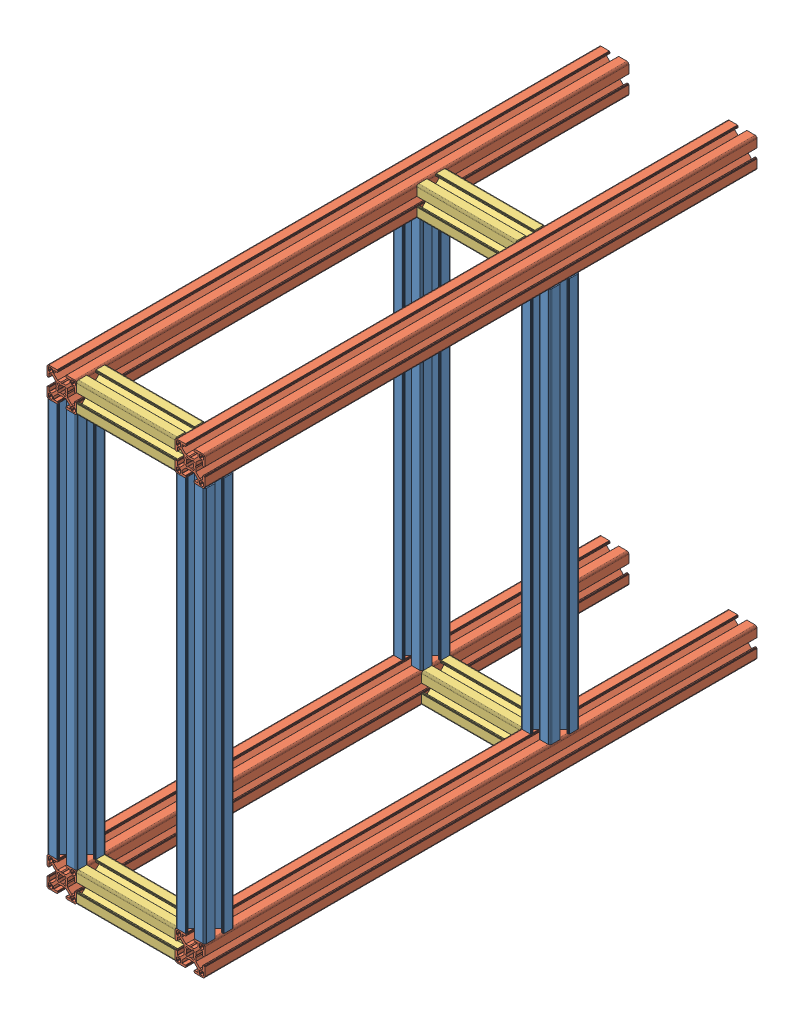
SolidWorks assembly module5_frame_v1.0, configuration Default. Lengths in mm.
Overall size (160 460 560).
12 component instances, 3 part files, 35 mates.
Components (placement in the parent):
- Profile_30x30mm_400mm-1: Profile_30x30mm_400mm [Default] x (1 0 0) z (0 -1 0) size (30 30 400)
- Profile_30x30mm_400mm-3: Profile_30x30mm_400mm [Default] at (-130 0 0) x (1 0 0) z (0 -1 0) size (30 30 400)
- profile_30x30mm_560mm-8: profile_30x30mm_560mm [Default] at (0 -30 30) size (30 30 560)
- profile_30x30mm_560mm-10: profile_30x30mm_560mm [Default] at (-130 -30 30) size (30 30 560)
- profile_30x30mm_560mm-6: profile_30x30mm_560mm [Default] at (-130 400 30) size (30 30 560)
- Profile_30x30mm_400mm-4: Profile_30x30mm_400mm [Default] at (30 400 -350) x (-1 0 0) z (0 1 0) size (30 30 400)
- profile_30x30mm_560mm-9: profile_30x30mm_560mm [Default] at (0 400 30) size (30 30 560)
- Profile_30x30mm_100mm-10: Profile_30x30mm_100mm [Default] at (0 400 30) x (0 0 -1) z (1 0 0) size (30 30 100)
- Profile_30x30mm_100mm-4: Profile_30x30mm_100mm [Default] at (0 400 -315) x (0 0 -1) z (1 0 0) size (30 30 100)
- Profile_30x30mm_100mm-11: Profile_30x30mm_100mm [Default] at (0 0 30) x (0 -1 0) z (1 0 0) size (30 30 100)
- Profile_30x30mm_100mm-9: Profile_30x30mm_100mm [Default] at (0 -30 -320) x (0 0 -1) z (1 0 0) size (30 30 100)
- Profile_30x30mm_400mm-5: Profile_30x30mm_400mm [Default] at (-130 0 -350) x (1 0 0) z (0 -1 0) size (30 30 400)
Mates (geometry in assembly coordinates):
- Coincident1: coincident: plane of Profile_30x30mm_400mm-1 through (0 400 0) normal (0 1 0); plane of ? through (-283.2452 400 0) normal (0 1 0)
- Coincident7: coincident: plane of Profile_30x30mm_400mm-1 through (10.25 400 30) normal (0 0 1); plane of ? through (-255.2452 400 30) normal (0 0 1)
- Coincident25: coincident: plane of profile_30x30mm_560mm-8 through (0 -30 30) normal (0 0 1); plane of ? through (-283.2452 -30 30) normal (0 0 1)
- Coincident26: coincident: plane of ? through (-283.2452 -30 30) normal (0 0 1); plane of ? through (-283.2452 400 30) normal (0 0 1)
- Coincident27: coincident: plane of ? through (-253.2452 -10.25 -530) normal (1 0 0); plane of ? through (-253.2452 419.75 -530) normal (1 0 0)
- Coincident30: coincident: plane of profile_30x30mm_560mm-8 through (10.25 0 -530) normal (0 1 0); plane of ? through (-272.9952 0 -530) normal (0 1 0)
- Coincident32: coincident: plane of assembly; plane of assembly; plane of Profile_30x30mm_400mm-1 through (30 400 2) normal (1 0 0); plane of profile_30x30mm_560mm-8 through (30 -28 -530) normal (1 0 0)
- Coincident35: coincident: plane of ? through (-283.2452 400 10.25) normal (-1 0 0); plane of ? through (-283.2452 428 -530) normal (-1 0 0)
- Coincident69: coincident: plane of assembly through (0 0 0) normal (0 1 0); plane of Profile_30x30mm_400mm-1 through (0 0 0) normal (0 -1 0); plane of assembly
- Coincident70: coincident: plane of assembly through (0 0 0) normal (0 0 1); plane of Profile_30x30mm_400mm-1 through (0 0 0) normal (0 0 1); plane of assembly
- Coincident71: coincident: plane of assembly through (0 0 0) normal (1 0 0); plane of Profile_30x30mm_400mm-1 through (0 0 0) normal (1 0 0); plane of assembly
- Coincident81: coincident: plane of assembly; plane of assembly; plane of Profile_30x30mm_400mm-1 through (30 400 19.75) normal (1 0 0); plane of profile_30x30mm_560mm-9 through (30 419.75 -530) normal (1 0 0)
- Distance36: distance = 30 mm: plane of assembly; plane of assembly; plane of Profile_30x30mm_400mm-1 through (0 0 0) normal (0 -1 0); plane of profile_30x30mm_560mm-8 through (19.75 -30 -530) normal (0 -1 0)
- Distance37: distance = 30 mm: plane of assembly; plane of assembly; plane of Profile_30x30mm_400mm-1 through (19.75 400 0) normal (0 0 -1); plane of profile_30x30mm_560mm-8 through (0 -30 30) normal (0 0 1)
- Distance38: distance = 30 mm: plane of assembly; plane of assembly; plane of Profile_30x30mm_400mm-1 through (19.75 400 0) normal (0 0 -1); plane of profile_30x30mm_560mm-9 through (0 400 30) normal (0 0 1)
- Distance39: distance = 30 mm: plane of assembly; plane of assembly; plane of Profile_30x30mm_400mm-3 through (-130 400 0) normal (0 1 0); plane of profile_30x30mm_560mm-6 through (-102 430 -530) normal (0 1 0)
- Distance40: distance = 30 mm: plane of assembly; plane of assembly; plane of Profile_30x30mm_400mm-1 through (0 400 0) normal (0 1 0); plane of profile_30x30mm_560mm-9 through (10.25 430 -530) normal (0 1 0)
- Coincident114: coincident: plane of assembly; plane of assembly; plane of profile_30x30mm_560mm-8 through (28 0 -530) normal (0 1 0); plane of Profile_30x30mm_400mm-4 through (30 0 -350) normal (0 -1 0)
- Coincident115: coincident: plane of assembly; plane of assembly; plane of profile_30x30mm_560mm-8 through (30 -10.25 -530) normal (1 0 0); plane of Profile_30x30mm_400mm-4 through (30 0 -339.75) normal (1 0 0)
- Coincident118: coincident: point of ?; plane of ? through (-253.2452 400 -315) normal (-1 0 0)
- Coincident119: coincident: plane of ? through (-253.2452 400 30) normal (-1 0 0); plane of ? through (-253.2452 400 -315) normal (-1 0 0)
- Coincident120: coincident: plane of ? through (-253.2452 419.75 -530) normal (1 0 0); plane of ? through (-253.2452 400 -315) normal (-1 0 0)
- Coincident123: coincident: plane of ? through (-253.2452 400 28) normal (0 -1 0); plane of ? through (-253.2452 400 -334.75) normal (0 -1 0)
- Coincident126: coincident: plane of ? through (-272.9952 430 -530) normal (0 1 0); plane of ? through (-253.2452 430 -325.25) normal (0 1 0)
- Coincident141: coincident: plane of ? through (-253.2452 -19.75 30) normal (0 0 1); plane of ? through (-283.2452 -30 30) normal (0 0 1)
- Coincident142: coincident: plane of ? through (-281.2452 -30 -530) normal (0 -1 0); plane of ? through (-253.2452 -30 28) normal (0 -1 0)
- Coincident143: coincident: plane of ? through (-253.2452 -28 -530) normal (1 0 0); plane of ? through (-253.2452 0 30) normal (-1 0 0)
- Distance45: distance = 185 mm: plane of assembly; plane of assembly; plane of Profile_30x30mm_100mm-4 through (-100 419.75 -345) normal (0 0 -1); plane of profile_30x30mm_560mm-6 through (-130 400 -530) normal (0 0 -1)
- Coincident163: coincident: plane of ? through (-253.2452 -10.25 -530) normal (1 0 0); plane of ? through (-253.2452 -30 -320) normal (-1 0 0)
- Distance50: distance = 180 mm: plane of assembly; plane of assembly; plane of Profile_30x30mm_100mm-9 through (-100 -28 -350) normal (0 0 -1); plane of profile_30x30mm_560mm-10 through (-130 -30 -530) normal (0 0 -1)
- Coincident186: coincident: plane of ? through (-255.2452 0 -530) normal (0 1 0); plane of ? through (-283.2452 0 -350) normal (0 -1 0)
- Coincident187: coincident: plane of ? through (-283.2452 -2 -530) normal (-1 0 0); plane of ? through (-283.2452 400 -339.75) normal (-1 0 0)
- Coincident188: coincident: plane of ? through (-253.2452 -19.75 -320) normal (0 0 1); plane of ? through (-255.2452 400 -320) normal (0 0 1)
- Coincident189: coincident: plane of Profile_30x30mm_400mm-4 through (2 0 -320) normal (0 0 1); plane of ? through (-253.2452 -19.75 -320) normal (0 0 1)
- Coincident190: coincident: plane of assembly; plane of assembly; plane of profile_30x30mm_560mm-9 through (0 428 -530) normal (-1 0 0); plane of Profile_30x30mm_100mm-4 through (0 400 -315) normal (1 0 0)
